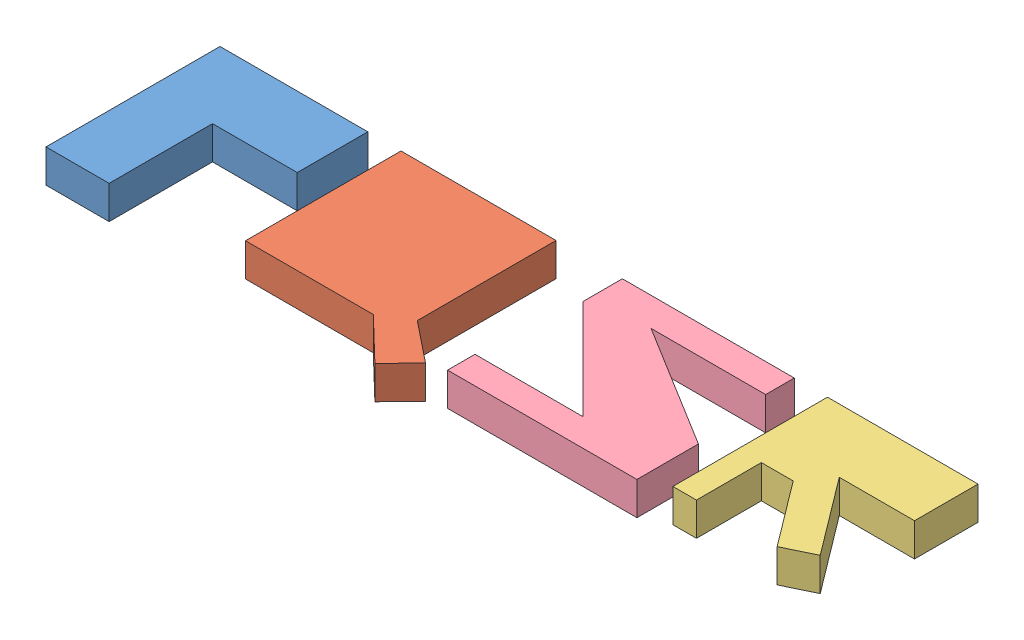
SolidWorks assembly PQRS, configuration Default. Lengths in mm.
Overall size (228.52 10 59.43).
4 component instances, 4 part files, 9 mates.
Components (placement in the parent):
- P-1: P [Default] at origin size (44.57 10 52.46)
- Q-1: Q [Default] at (54.569 0 -5.5748) size (59.05 10 59.43)
- R-1: R [Default] at (183.144 0 -5.8481) size (45.38 10 46.61)
- S-1: S [Default] at (173.144 0 -52.4562) size (57.09 10 50.2)
Mates (geometry in assembly coordinates):
- Coincident1: coincident aligned: plane of P-1 through (0 10 0) normal (0 1 0); plane of Q-1 through (54.569 10 -5.5748) normal (0 1 0)
- Distance1: distance = 10 mm anti-aligned: plane of P-1 through (44.569 10 -52.4562) normal (1 0 0); plane of Q-1 through (54.569 10 -5.5748) normal (-1 0 0)
- Coincident4: coincident aligned: plane of P-1 through (0 10 -52.4562) normal (0 0 -1); plane of Q-1 through (54.569 10 -52.4562) normal (0 0 -1)
- Coincident5: coincident aligned: plane of Q-1 through (54.569 10 -5.5748) normal (0 1 0); plane of S-1 through (173.144 10 -52.4562) normal (0 1 0)
- Coincident6: coincident aligned: plane of Q-1 through (54.569 10 -52.4562) normal (0 0 -1); plane of S-1 through (173.144 10 -52.4562) normal (0 0 -1)
- Distance2: distance = 20 mm anti-aligned: plane of S-1 through (121.3138 10 -52.4562) normal (-1 0 0); plane of Q-1 through (101.3138 10 -52.4562) normal (1 0 0)
- Coincident9: coincident: plane of R-1 through (183.144 10 -1.3422) normal (0 1 0); plane of S-1 through (173.144 10 -52.4562) normal (0 1 0)
- Distance3: distance = 10 mm: plane of S-1 through (173.144 10 -43.8178) normal (1 0 0); plane of R-1 through (183.144 10 -5.8481) normal (-1 0 0)
- Coincident11: coincident aligned: plane of R-1 through (183.144 10 -52.4562) normal (0 0 -1); plane of S-1 through (173.144 10 -52.4562) normal (0 0 -1)
